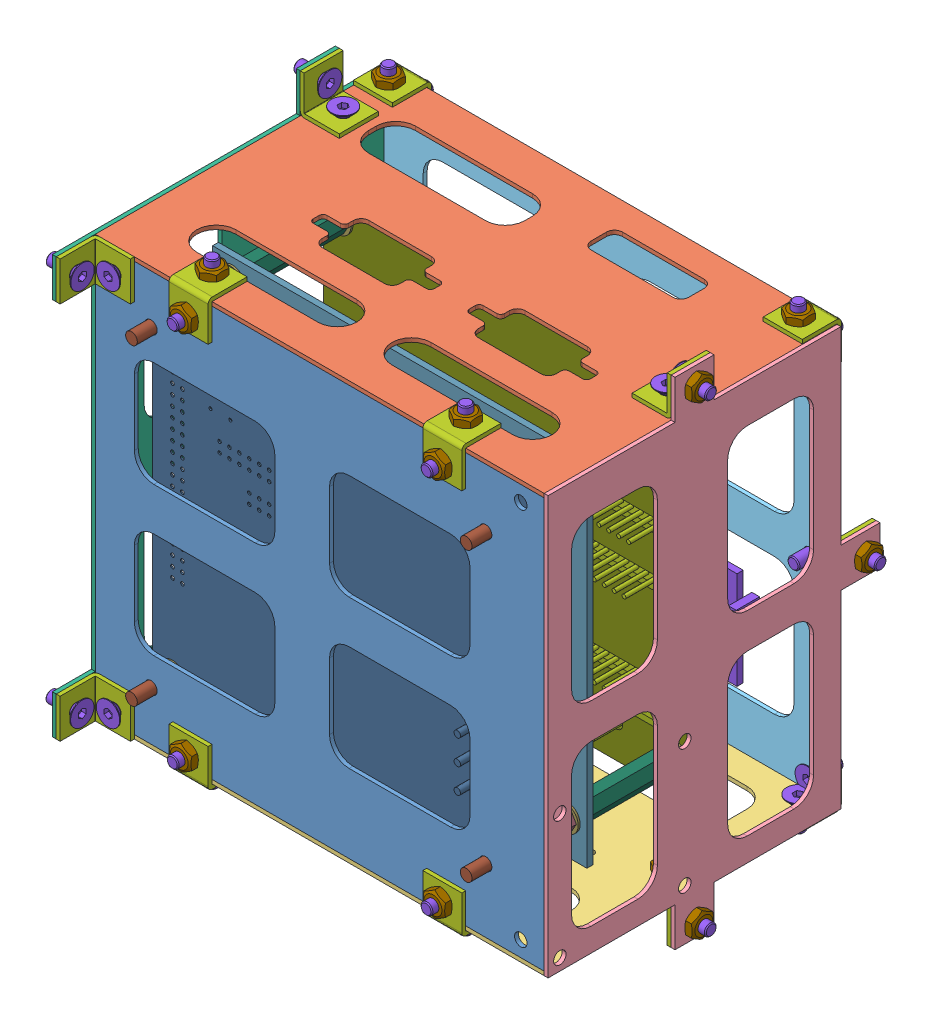
SolidWorks assembly avionics_reassemb, configuration Default. Lengths in mm.
Overall size (125.66 127 95).
175 component instances, 45 part files, 0 mates.
Components (placement in the parent):
- PCB_board_box_reassemb-1: PCB_board_box_reassemb [Default] at origin size (125.66 127 95)
  - PCB_board_box_buttom-1: PCB_board_box_buttom [Default] at origin size (115 105 1)
  - PCB_board_box_front-1: PCB_board_box_front [Default] at (0 53.5 -36.5) x (0 0 -1) z (0 -1 0) size (75 115 1)
  - PCB_board_box_back-1: PCB_board_box_back [Default] at (0 -53.5 -36.5) x (0 0 1) z (0 1 0) size (75 115 1)
  - PCB_board_box_right-1: PCB_board_box_right [Default] at (58.5 0 -36.5) x (0 0 1) z (-1 0 0) size (85 127 1)
  - PCB_board_box_top-1: PCB_board_box_top [Default] at (0 0 -74) x (0 -1 0) z (0 0 1) size (105 115 1)
  - PCB_board_box_left-1: PCB_board_box_left [Default] at (-57.5 0 -36.5) x (0 0 1) z (-1 0 0) size (85 127 1)
  - connector_1-1: connector_1 [Default] at (-32.5 49.6 2.1) x (1 0 0) z (0 0 -1) size (10 10 10)
  - connector_1-2: connector_1 [Default] at (57.5 58.5 -36.5) x (0 0 1) z (-1 0 0) size (10 10 10)
  - connector_1-3: connector_1 [Default] at (57.5 -58.5 -36.5) x (0 0 -1) z (-1 0 0) size (10 10 10)
  - connector_1-4: connector_1 [Default] at (32.5 -49.6 2.1) x (-1 0 0) z (0 0 -1) size (10 10 10)
  - connector_1-5: connector_1 [Default] at (-32.5 -49.6 2.1) x (-1 0 0) z (0 0 -1) size (10 10 10)
  - connector_1-6: connector_1 [Default] at (-57.5 48.5 6) x (0 1 0) z (1 0 0) size (10 10 10)
  - connector_1-7: connector_1 [Default] at (-57.5 -48.5 6) x (0 1 0) z (1 0 0) size (10 10 10)
  - connector_1-8: connector_1 [Default] at (-57.5 58.5 -56.5) x (0 0 -1) z (1 0 0) size (10 10 10)
  - connector_1-9: connector_1 [Default] at (-57.5 -58.5 -56.5) x (0 0 1) z (1 0 0) size (10 10 10)
  - connector_1-10: connector_1 [Default] at (52.5 0 -74) x (0 -1 0) z (0 0 -1) size (10 10 10)
  - connector_1-11: connector_1 [Default] at (52.5 -49.6 -75.1) size (10 10 10)
  - connector_1-12: connector_1 [Default] at (-52.5 -54.6 -70.1) x (-1 0 0) z (0 1 0) size (10 10 10)
  - connector_1-13: connector_1 [Default] at (-52.5 49.6 -75.1) x (-1 0 0) z (0 0 1) size (10 10 10)
  - connector_1-14: connector_1 [Default] at (32.5 49.6 2.1) x (1 0 0) z (0 0 -1) size (10 10 10)
  - connector_1-15: connector_1 [Default] at (52.5 49.6 -75.1) x (-1 0 0) z (0 0 1) size (10 10 10)
  - ISO 10642 - M3 x  8-1: ISO 10642 - M3 x  8 [Default] at (-52.5 48.6 -71.3293) x (0 0 -1) z (-1 0 0) size (8 6 6)
  - ISO 10642 - M3 x  8-2: ISO 10642 - M3 x  8 [Default] at (-52.5 50.8293 -69.1) x (0 1 0) z (-1 0 0) size (8 6 6)
  - ISO 10642 - M3 x  8-3: ISO 10642 - M3 x  8 [Default] at (-52.5 -48.6 -71.3293) x (0 0 -1) z (-1 0 0) size (8 6 6)
  - ISO 10642 - M3 x  8-4: ISO 10642 - M3 x  8 [Default] at (-52.5 -50.8293 -69.1) x (0 -1 0) z (-1 0 0) size (8 6 6)
  - ISO 10642 - M3 x  8-5: ISO 10642 - M3 x  8 [Default] at (52.5 -50.7586 -69.1) x (0 -1 0) z (-1 0 0) size (8 6 6)
  - ISO 10642 - M3 x  8-6: ISO 10642 - M3 x  8 [Default] at (52.5 -48.6 -71.2586) x (0 0 -1) z (-1 0 0) size (8 6 6)
  - ISO 10642 - M3 x  8-7: ISO 10642 - M3 x  8 [Default] at (32.5 -48.6 -1.7414) x (0 0 1) z (-1 0 0) size (8 6 6)
  - ISO 10642 - M3 x  8-8: ISO 10642 - M3 x  8 [Default] at (32.5 -50.7586 -3.9) x (0 -1 0) z (-1 0 0) size (8 6 6)
  - ISO 10642 - M3 x  8-9: ISO 10642 - M3 x  8 [Default] at (-32.5 -48.6 -1.7414) x (0 0 1) z (-1 0 0) size (8 6 6)
  - ISO 10642 - M3 x  8-10: ISO 10642 - M3 x  8 [Default] at (-32.5 -50.7586 -3.9) x (0 -1 0) z (-1 0 0) size (8 6 6)
  - ISO 10642 - M3 x  8-11: ISO 10642 - M3 x  8 [Default] at (32.5 48.6 -1.7414) x (0 0 1) z (-1 0 0) size (8 6 6)
  - ISO 10642 - M3 x  8-12: ISO 10642 - M3 x  8 [Default] at (32.5 50.7586 -3.9) x (0 1 0) z (-1 0 0) size (8 6 6)
  - ISO 10642 - M3 x  8-13: ISO 10642 - M3 x  8 [Default] at (-32.5 48.6 -1.6707) x (0 0 1) z (-1 0 0) size (8 6 6)
  - ISO 10642 - M3 x  8-14: ISO 10642 - M3 x  8 [Default] at (-32.5 50.7586 -3.9) x (0 1 0) z (-1 0 0) size (8 6 6)
  - ISO 10642 - M3 x  8-15: ISO 10642 - M3 x  8 [Default] at (52.5 48.6 -71.2586) x (0 0 -1) z (-1 0 0) size (8 6 6)
  - ISO 10642 - M3 x  8-16: ISO 10642 - M3 x  8 [Default] at (52.5 50.7586 -69.1) x (0 1 0) z (-1 0 0) size (8 6 6)
  - ISO 10642 - M3 x  8-17: ISO 10642 - M3 x  8 [Default] at (51.5 0 -76.7414) x (0 0 1) z (-1 0 0) size (8 6 6)
  - ISO 10642 - M3 x  8-18: ISO 10642 - M3 x  8 [Default] at (54.7586 0 -80) x (1 0 0) z (0 0 -1) size (8 6 6)
  - ISO 10642 - M3 x  8-19: ISO 10642 - M3 x  8 [Default] at (54.7586 -59.5 -36.5) x (1 0 0) z (0 0 -1) size (8 6 6)
  - ISO 10642 - M3 x  8-20: ISO 10642 - M3 x  8 [Default] at (51.5 -56.2414 -36.5) x (0 1 0) z (-1 0 0) size (8 6 6)
  - ISO 10642 - M3 x  8-21: ISO 10642 - M3 x  8 [Default] at (51.5 56.2414 -36.5) x (0 -1 0) z (-1 0 0) size (8 6 6)
  - ISO 10642 - M3 x  8-22: ISO 10642 - M3 x  8 [Default] at (54.8293 59.5 -36.5) x (1 0 0) z (0 0 -1) size (8 6 6)
  - ISO 10642 - M3 x  8-23: ISO 10642 - M3 x  8 [Default] at (-51.5 56.1707 -56.5) x (0 -1 0) z (-1 0 0) size (8 6 6)
  - ISO 10642 - M3 x  8-24: ISO 10642 - M3 x  8 [Default] at (-54.8293 59.5 -56.5) x (-1 0 0) z (0 0 1) size (8 6 6)
  - ISO 10642 - M3 x  8-25: ISO 10642 - M3 x  8 [Default] at (-51.5 48.5 3.7414) x (0 0 -1) z (-1 0 0) size (8 6 6)
  - ISO 10642 - M3 x  8-26: ISO 10642 - M3 x  8 [Default] at (-54.7586 48.5 7) x (-1 0 0) z (0 0 1) size (8 6 6)
  - ISO 10642 - M3 x  8-27: ISO 10642 - M3 x  8 [Default] at (-54.8293 -48.5 7) x (-1 0 0) z (0 0 1) size (8 6 6)
  - ISO 10642 - M3 x  8-28: ISO 10642 - M3 x  8 [Default] at (-51.5 -48.5 3.7414) x (0 0 -1) z (-1 0 0) size (8 6 6)
  - ISO 10642 - M3 x  8-29: ISO 10642 - M3 x  8 [Default] at (-54.7586 -59.5 -56.5) x (-1 0 0) z (0 0 1) size (8 6 6)
  - ISO 10642 - M3 x  8-30: ISO 10642 - M3 x  8 [Default] at (-51.5 -56.1707 -56.5) x (0 1 0) z (-1 0 0) size (8 6 6)
  - ISO 4032 - M3-1: ISO 4032 - M3 [Default] at (-52.5 48.6 -77.5) x (0 0 1) z (-1 0 0) size (2.4 6.35 5.5)
  - ISO 4032 - M3-2: ISO 4032 - M3 [Default] at (-52.5 54.6 -69.1) x (0 1 0) z (-1 0 0) size (2.4 6.35 5.5)
  - ISO 4032 - M3-3: ISO 4032 - M3 [Default] at (-51.5 52.5 -56.5) x (0 -1 0) z (-1 0 0) size (2.4 6.35 5.5)
  - ISO 4032 - M3-4: ISO 4032 - M3 [Default] at (-52.5 -48.6 -75.1) x (0 0 -1) z (-1 0 0) size (2.4 6.35 5.5)
  - ISO 4032 - M3-5: ISO 4032 - M3 [Default] at (-52.5 -54.6 -69.1) x (0 -1 0) z (-1 0 0) size (2.4 6.35 5.5)
  - ISO 4032 - M3-6: ISO 4032 - M3 [Default] at (-51.5 -52.5 -56.5) x (0 1 0) z (-1 0 0) size (2.4 6.35 5.5)
  - ISO 4032 - M3-7: ISO 4032 - M3 [Default] at (-51.5 -48.5 0) x (0 0 -1) z (-1 0 0) size (2.4 6.35 5.5)
  - ISO 4032 - M3-8: ISO 4032 - M3 [Default] at (-51.5 48.5 0) x (0 0 -1) z (-1 0 0) size (2.4 6.35 5.5)
  - ISO 4032 - M3-9: ISO 4032 - M3 [Default] at (-32.5 57 -3.9) x (0 -1 0) z (-1 0 0) size (2.4 6.35 5.5)
  - ISO 4032 - M3-10: ISO 4032 - M3 [Default] at (-32.5 48.6 4.5) x (0 0 -1) z (-1 0 0) size (2.4 6.35 5.5)
  - ISO 4032 - M3-11: ISO 4032 - M3 [Default] at (-32.5 -48.6 2.1) x (0 0 1) z (-1 0 0) size (2.4 6.35 5.5)
  - ISO 4032 - M3-12: ISO 4032 - M3 [Default] at (-32.5 -57 -3.9) x (0 1 0) z (-1 0 0) size (2.4 6.35 5.5)
  - ISO 4032 - M3-13: ISO 4032 - M3 [Default] at (52.5 -48.6 -75.1) x (0 0 -1) z (-1 0 0) size (2.4 6.35 5.5)
  - ISO 4032 - M3-14: ISO 4032 - M3 [Default] at (52.5 -54.6 -69.1) x (0 -1 0) z (-1 0 0) size (2.4 6.35 5.5)
  - ISO 4032 - M3-15: ISO 4032 - M3 [Default] at (52.5 48.6 -75.1) x (0 0 -1) z (-1 0 0) size (2.4 6.35 5.5)
  - ISO 4032 - M3-16: ISO 4032 - M3 [Default] at (52.5 54.6 -69.1) x (0 1 0) z (-1 0 0) size (2.4 6.35 5.5)
  - ISO 4032 - M3-17: ISO 4032 - M3 [Default] at (32.5 57 -3.9) x (0 -1 0) z (-1 0 0) size (2.4 6.35 5.5)
  - ISO 4032 - M3-18: ISO 4032 - M3 [Default] at (32.5 48.6 4.5) x (0 0 -1) z (-1 0 0) size (2.4 6.35 5.5)
  - ISO 4032 - M3-19: ISO 4032 - M3 [Default] at (32.5 -48.6 4.5) x (0 0 -1) z (-1 0 0) size (2.4 6.35 5.5)
  - ISO 4032 - M3-20: ISO 4032 - M3 [Default] at (32.5 -57 -3.9) x (0 1 0) z (-1 0 0) size (2.4 6.35 5.5)
  - ISO 4032 - M3-21: ISO 4032 - M3 [Default] at (51.5 -52.5 -36.5) x (0 1 0) z (-1 0 0) size (2.4 6.35 5.5)
  - ISO 4032 - M3-22: ISO 4032 - M3 [Default] at (51.5 52.5 -36.5) x (0 -1 0) z (-1 0 0) size (2.4 6.35 5.5)
  - ISO 4032 - M3-23: ISO 4032 - M3 [Default] at (58.5 0 -80) size (2.4 6.35 5.5)
  - ISO 4032 - M3-24: ISO 4032 - M3 [Default] at (58.5 -59.5 -36.5) size (2.4 6.35 5.5)
  - ISO 4032 - M3-25: ISO 4032 - M3 [Default] at (58.5 59.5 -36.5) size (2.4 6.35 5.5)
- PCB-1: PCB [Default] at (47.58 -45.05 -4.8556) x (0 1 0) z (0 0 -1) size (90.17 95.89 17.8)
- copper_pillar_M3_L15-1: copper_pillar_M3_L15 [Default] at (42.5 -36.16 0) x (1 0 0) z (0 1 0) size (5.77 16 5)
- copper_pillar_M3_L15-2: copper_pillar_M3_L15 [Default] at (-43.225 40.04 0) x (1 0 0) z (0 1 0) size (5.77 16 5)
- copper_pillar_M3_L15-3: copper_pillar_M3_L15 [Default] at (42.5 37.5 0) x (1 0 0) z (0 1 0) size (5.77 16 5)
- copper_pillar_M3_L15-4: copper_pillar_M3_L15 [Default] at (-43.225 -39.97 0) x (1 0 0) z (0 1 0) size (5.77 16 5)
- washerM3x0.5h-1: washerM3x0.5h [Default] at (-43.225 -39.97 -4.5) size (6.7 6.7 0.5)
- washerM3x0.5h-2: washerM3x0.5h [Default] at (42.5 -36.16 -4.5) size (6.7 6.7 0.5)
- washerM3x0.5h-3: washerM3x0.5h [Default] at (-43.225 40.04 -4) x (1 0 0) z (0 0 -1) size (6.7 6.7 0.5)
- washerM3x0.5h-4: washerM3x0.5h [Default] at (42.5 37.5 -4) x (1 0 0) z (0 0 -1) size (6.7 6.7 0.5)
- copper_pillar_M3_L15_1-1: copper_pillar_M3_L15_1 [Default] at (42.5 -36.16 -5.3556) x (1 0 0) z (0 1 0) size (5.77 26 5)
- copper_pillar_M3_L15_1-2: copper_pillar_M3_L15_1 [Default] at (42.5 37.5 -5.3556) x (1 0 0) z (0 1 0) size (5.77 26 5)
- copper_pillar_M3_L15_1-3: copper_pillar_M3_L15_1 [Default] at (-43.225 40.04 -5.3556) x (1 0 0) z (0 1 0) size (5.77 26 5)
- copper_pillar_M3_L15_1-4: copper_pillar_M3_L15_1 [Default] at (-43.225 -39.97 -5.3556) x (1 0 0) z (0 1 0) size (5.77 26 5)
- washerM3x0.5h-5: washerM3x0.5h [Default] at (-43.225 40.04 -5.3556) size (6.7 6.7 0.5)
- washerM3x0.5h-6: washerM3x0.5h [Default] at (-43.225 -39.97 -4.8556) x (1 0 0) z (0 0 -1) size (6.7 6.7 0.5)
- washerM3x0.5h-7: washerM3x0.5h [Default] at (42.5 -36.16 -4.8556) x (1 0 0) z (0 0 -1) size (6.7 6.7 0.5)
- washerM3x0.5h-8: washerM3x0.5h [Default] at (42.5 37.5 -4.8556) x (1 0 0) z (0 0 -1) size (6.7 6.7 0.5)
- washerM3x0.5h-9: washerM3x0.5h [Default] at (-43.225 40.04 -19.3556) x (1 0 0) z (0 0 -1) size (6.7 6.7 0.5)
- washerM3x0.5h-10: washerM3x0.5h [Default] at (-43.225 -39.97 -19.3556) x (1 0 0) z (0 0 -1) size (6.7 6.7 0.5)
- washerM3x0.5h-11: washerM3x0.5h [Default] at (42.5 -36.16 -19.3556) x (1 0 0) z (0 0 -1) size (6.7 6.7 0.5)
- washerM3x0.5h-12: washerM3x0.5h [Default] at (42.5 37.5 -19.3556) x (1 0 0) z (0 0 -1) size (6.7 6.7 0.5)
- STM32 Communication Board ver1.0-1: STM32 Communication Board ver1.0 [Default] at (42.5 -36.16 -21.3601) x (0 1 0) z (0 0 -1) size (90.17 95.89 10)
- washerM3x0.5h-13: washerM3x0.5h [Default] at (42.5 -36.16 -21.3601) x (1 0 0) z (0 0 -1) size (6.7 6.7 0.5)
- washerM3x0.5h-14: washerM3x0.5h [Default] at (-43.225 -39.97 -21.3601) x (1 0 0) z (0 0 -1) size (6.7 6.7 0.5)
- washerM3x0.5h-15: washerM3x0.5h [Default] at (42.5 37.5 -21.3601) x (1 0 0) z (0 0 -1) size (6.7 6.7 0.5)
- washerM3x0.5h-16: washerM3x0.5h [Default] at (-43.225 40.04 -21.3601) x (1 0 0) z (0 0 -1) size (6.7 6.7 0.5)
- copper_pillar_M3_L25_1-1: copper_pillar_M3_L25_1 [Default] at (-43.225 -39.97 -21.8601) x (1 0 0) z (0 1 0) size (5.77 37 5)
- copper_pillar_M3_L25_1-2: copper_pillar_M3_L25_1 [Default] at (42.5 -36.16 -21.8601) x (1 0 0) z (0 1 0) size (5.77 37 5)
- copper_pillar_M3_L25_1-3: copper_pillar_M3_L25_1 [Default] at (42.5 37.5 -21.8601) x (1 0 0) z (0 1 0) size (5.77 37 5)
- copper_pillar_M3_L25_1-4: copper_pillar_M3_L25_1 [Default] at (-43.225 40.04 -21.8601) x (1 0 0) z (0 1 0) size (5.77 37 5)
- washerM3x0.5h-17: washerM3x0.5h [Default] at (42.5 37.5 -47.3601) size (6.7 6.7 0.5)
- washerM3x0.5h-18: washerM3x0.5h [Default] at (-43.225 40.04 -46.8601) x (1 0 0) z (0 0 -1) size (6.7 6.7 0.5)
- washerM3x0.5h-19: washerM3x0.5h [Default] at (42.5 -36.16 -47.3601) size (6.7 6.7 0.5)
- washerM3x0.5h-20: washerM3x0.5h [Default] at (-43.225 -39.97 -47.3601) size (6.7 6.7 0.5)
- empty_board-1: empty_board [Default] at (0.08 0.12 -47.3601) x (0 1 0) z (-1 0 0) size (90 1.45 95)
- MTi-1_v3-1: MTi-1_v3 [Default] at (-8.5645 -18.7527 -51.9664) x (0 1 0) z (0 0 -1) size (53.34 66.07 22.31)
  - Board_1v2(2)^MTi-1-SoB_v2-1: Board_1v2(2)^MTi-1-SoB_v2 [Default] at origin size (12.15 12.15 1.56)
    - Open CASCADE STEP translator 6.8 2.1.1^Board_1v2(2)_MTi-1-SoB_v2-1: Open CASCADE STEP translator 6.8 2.1.1^Board_1v2(2)_MTi-1-SoB_v2 [Default] at (0 0 -1.5563) size (12.15 12.15 1.56)
      - Open CASCADE STEP translator 6.8 2.1.1.1^Open CASCADE STEP translator_ 6.8 2.1.1_Board_1v2(2)_MTi-1-SoB_v2-1: Open CASCADE STEP translator 6.8 2.1.1.1^Open CASCADE STEP translator_ 6.8 2.1.1_Board_1v2(2)_MTi-1-SoB_v2 [Default] at origin size (12.15 12.15 1.56)
  - U200_1v2(2)^MTi-1-SoB_v2-1: U200_1v2(2)^MTi-1-SoB_v2 [Default] at origin size (3.1 3.3 0.6)
    - 7460079024(2)^U200_1v2(2)_MTi-1-SoB_v2-1: 7460079024(2)^U200_1v2(2)_MTi-1-SoB_v2 [Default] at (5.6 3.4 0) size (3.1 3.3 0.6)
      - Extruded(2)^7460079024(2)_U200_1v2(2)_MTi-1-SoB_v2-1: Extruded(2)^7460079024(2)_U200_1v2(2)_MTi-1-SoB_v2 [Default] at origin size (3.1 3.3 0.6)
  - C200_1v2(2)^MTi-1-SoB_v2-1: C200_1v2(2)^MTi-1-SoB_v2 [Default] at origin size (1.05 0.55 0.55)
    - Cap_0402(2)^C200_1v2(2)_MTi-1-SoB_v2-1: Cap_0402(2)^C200_1v2(2)_MTi-1-SoB_v2 [Default] at (5.3999 6.9749 0.26) x (-1 0 0) z (0 0 1) size (1.05 0.55 0.55)
  - C201_1v2(2)^MTi-1-SoB_v2-1: C201_1v2(2)^MTi-1-SoB_v2 [Default] at origin size (1.05 0.55 0.55)
    - Cap_0402(2)^C201_1v2(2)_MTi-1-SoB_v2-1: Cap_0402(2)^C201_1v2(2)_MTi-1-SoB_v2 [Default] at (6.7999 1.375 0.26) x (-1 0 0) z (0 0 1) size (1.05 0.55 0.55)
  - C204_1v2(2)^MTi-1-SoB_v2-1: C204_1v2(2)^MTi-1-SoB_v2 [Default] at origin size (1.05 0.55 0.55)
    - Cap_0402(2)^C204_1v2(2)_MTi-1-SoB_v2-1: Cap_0402(2)^C204_1v2(2)_MTi-1-SoB_v2 [Default] at (8.1999 3.0749 0.26) x (-1 0 0) z (0 0 1) size (1.05 0.55 0.55)
  - C205_1v2(2)^MTi-1-SoB_v2-1: C205_1v2(2)^MTi-1-SoB_v2 [Default] at origin size (1.05 0.55 0.55)
    - Cap_0402(2)^C205_1v2(2)_MTi-1-SoB_v2-1: Cap_0402(2)^C205_1v2(2)_MTi-1-SoB_v2 [Default] at (4.2001 0.8251 0.26) x (1 0 0) z (0 0 1) size (1.05 0.55 0.55)
  - C206_1v2(2)^MTi-1-SoB_v2-1: C206_1v2(2)^MTi-1-SoB_v2 [Default] at origin size (0.55 1.05 0.55)
    - Cap_0402(2)^C206_1v2(2)_MTi-1-SoB_v2-1: Cap_0402(2)^C206_1v2(2)_MTi-1-SoB_v2 [Default] at (3.1251 4.5999 0.26) x (0 -1 0) z (0 0 1) size (1.05 0.55 0.55)
  - C207_1v2(2)^MTi-1-SoB_v2-1: C207_1v2(2)^MTi-1-SoB_v2 [Default] at origin size (1.05 0.55 0.55)
    - Cap_0402(2)^C207_1v2(2)_MTi-1-SoB_v2-1: Cap_0402(2)^C207_1v2(2)_MTi-1-SoB_v2 [Default] at (7.3001 5.4251 0.26) x (1 0 0) z (0 0 1) size (1.05 0.55 0.55)
  - C208_1v2(2)^MTi-1-SoB_v2-1: C208_1v2(2)^MTi-1-SoB_v2 [Default] at origin size (0.55 1.05 0.55)
    - Cap_0402(2)^C208_1v2(2)_MTi-1-SoB_v2-1: Cap_0402(2)^C208_1v2(2)_MTi-1-SoB_v2 [Default] at (3.1251 2.5999 0.26) x (0 -1 0) z (0 0 1) size (1.05 0.55 0.55)
  - C209_1v2(2)^MTi-1-SoB_v2-1: C209_1v2(2)^MTi-1-SoB_v2 [Default] at origin size (1.05 0.55 0.55)
    - Cap_0402(2)^C209_1v2(2)_MTi-1-SoB_v2-1: Cap_0402(2)^C209_1v2(2)_MTi-1-SoB_v2 [Default] at (8.6001 1.4251 0.26) x (1 0 0) z (0 0 1) size (1.05 0.55 0.55)
  - C300_1v2(2)^MTi-1-SoB_v2-1: C300_1v2(2)^MTi-1-SoB_v2 [Default] at origin size (0.55 1.05 0.55)
    - Cap_0402(2)^C300_1v2(2)_MTi-1-SoB_v2-1: Cap_0402(2)^C300_1v2(2)_MTi-1-SoB_v2 [Default] at (10.425 8.2999 0.26) x (0 -1 0) z (0 0 1) size (1.05 0.55 0.55)
  - C301_1v2(2)^MTi-1-SoB_v2-1: C301_1v2(2)^MTi-1-SoB_v2 [Default] at origin size (1.05 0.55 0.55)
    - Cap_0402(2)^C301_1v2(2)_MTi-1-SoB_v2-1: Cap_0402(2)^C301_1v2(2)_MTi-1-SoB_v2 [Default] at (3.4001 10.375 0.26) x (1 0 0) z (0 0 1) size (1.05 0.55 0.55)
  - C302_1v2(2)^MTi-1-SoB_v2-1: C302_1v2(2)^MTi-1-SoB_v2 [Default] at origin size (1.05 0.55 0.55)
    - Cap_0402(2)^C302_1v2(2)_MTi-1-SoB_v2-1: Cap_0402(2)^C302_1v2(2)_MTi-1-SoB_v2 [Default] at (5.5999 8.0749 0.26) x (-1 0 0) z (0 0 1) size (1.05 0.55 0.55)
  - C303_1v2(2)^MTi-1-SoB_v2-1: C303_1v2(2)^MTi-1-SoB_v2 [Default] at origin size (1.05 0.55 0.55)
    - Cap_0402(2)^C303_1v2(2)_MTi-1-SoB_v2-1: Cap_0402(2)^C303_1v2(2)_MTi-1-SoB_v2 [Default] at (7.2999 6.9749 0.26) x (-1 0 0) z (0 0 1) size (1.05 0.55 0.55)
  - C305_1v2(2)^MTi-1-SoB_v2-1: C305_1v2(2)^MTi-1-SoB_v2 [Default] at origin size (0.55 1.05 0.55)
    - Cap_0402(2)^C305_1v2(2)_MTi-1-SoB_v2-1: Cap_0402(2)^C305_1v2(2)_MTi-1-SoB_v2 [Default] at (6.4749 9.3001 0.26) x (0 1 0) z (0 0 1) size (1.05 0.55 0.55)
  - C304_1v2(2)^MTi-1-SoB_v2-1: C304_1v2(2)^MTi-1-SoB_v2 [Default] at origin size (0.55 1.05 0.55)
    - Cap_0402(2)^C304_1v2(2)_MTi-1-SoB_v2-1: Cap_0402(2)^C304_1v2(2)_MTi-1-SoB_v2 [Default] at (5.4749 9.3001 0.26) x (0 1 0) z (0 0 1) size (1.05 0.55 0.55)
  - R200_1v2(2)^MTi-1-SoB_v2-1: R200_1v2(2)^MTi-1-SoB_v2 [Default] at origin size (1 0.5 0.35)
    - RES0402(2)^R200_1v2(2)_MTi-1-SoB_v2-1: RES0402(2)^R200_1v2(2)_MTi-1-SoB_v2 [Default] at (-16.787 18.2331 0) x (-1 0 0) z (0 1 0) size (1 0.35 0.5)
  - R300_1v2(2)^MTi-1-SoB_v2-1: R300_1v2(2)^MTi-1-SoB_v2 [Default] at origin size (0.5 1 0.35)
    - RES0402(2)^R300_1v2(2)_MTi-1-SoB_v2-1: RES0402(2)^R300_1v2(2)_MTi-1-SoB_v2 [Default] at (13.6331 30.587 0) x (0 1 0) z (1 0 0) size (1 0.35 0.5)
  - R301_1v2(2)^MTi-1-SoB_v2-1: R301_1v2(2)^MTi-1-SoB_v2 [Default] at origin size (0.5 1 0.35)
    - RES0402(2)^R301_1v2(2)_MTi-1-SoB_v2-1: RES0402(2)^R301_1v2(2)_MTi-1-SoB_v2 [Default] at (21.9331 28.487 0) x (0 1 0) z (1 0 0) size (1 0.35 0.5)
  - S300_1v2(2)^MTi-1-SoB_v2-1: S300_1v2(2)^MTi-1-SoB_v2 [Default] at origin size (3 3 1)
    - 6752205952(2)^S300_1v2(2)_MTi-1-SoB_v2-1: 6752205952(2)^S300_1v2(2)_MTi-1-SoB_v2 [Default] at (8.4999 8.8999 0) size (3 3 1)
      - Extruded-1(2)^6752205952(2)_S300_1v2(2)_MTi-1-SoB_v2-1: Extruded-1(2)^6752205952(2)_S300_1v2(2)_MTi-1-SoB_v2 [Default] at origin size (3 3 1)
  - S301_1v2(2)^MTi-1-SoB_v2-1: S301_1v2(2)^MTi-1-SoB_v2 [Default] at origin size (2.5 3 0.86)
    - User_Library-LGA-14_2_5x3(2)^S301_1v2(2)_MTi-1-SoB_v2-1: User_Library-LGA-14_2_5x3(2)^S301_1v2(2)_MTi-1-SoB_v2 [Default] at (3.1 8.3 0.85) x (0 -1 0) z (1 0 0) size (3 0.86 2.5)
  - R302_1v2(2)^MTi-1-SoB_v2-1: R302_1v2(2)^MTi-1-SoB_v2 [Default] at origin size (0.5 1 0.35)
    - RES0402(2)^R302_1v2(2)_MTi-1-SoB_v2-1: RES0402(2)^R302_1v2(2)_MTi-1-SoB_v2 [Default] at (22.9331 28.487 0) x (0 1 0) z (1 0 0) size (1 0.35 0.5)
  - C202_1v2(2)^MTi-1-SoB_v2-1: C202_1v2(2)^MTi-1-SoB_v2 [Default] at origin size (1.05 0.55 0.55)
    - Cap_0402(2)^C202_1v2(2)_MTi-1-SoB_v2-1: Cap_0402(2)^C202_1v2(2)_MTi-1-SoB_v2 [Default] at (8.2001 4.4251 0.26) x (1 0 0) z (0 0 1) size (1.05 0.55 0.55)
  - C203_1v2(2)^MTi-1-SoB_v2-1: C203_1v2(2)^MTi-1-SoB_v2 [Default] at origin size (1.05 0.55 0.55)
    - Cap_0402(2)^C203_1v2(2)_MTi-1-SoB_v2-1: Cap_0402(2)^C203_1v2(2)_MTi-1-SoB_v2 [Default] at (8.2001 3.4251 0.26) x (1 0 0) z (0 0 1) size (1.05 0.55 0.55)
  - Y200_1v2(2)^MTi-1-SoB_v2-1: Y200_1v2(2)^MTi-1-SoB_v2 [Default] at origin size (1.61 2.01 0.31)
    - User_Library-Crystal_(NDK)_2.0x1.6(2)^Y200_1v2(2)_MTi-1-SoB_v2-1: User_Library-Crystal_(NDK)_2.0x1.6(2)^Y200_1v2(2)_MTi-1-SoB_v2 [Default] at (10.2 4.0001 0) x (0 -1 0) z (-1 0 0) size (2.01 0.31 1.61)
  - R303_1v2(2)^MTi-1-SoB_v2-1: R303_1v2(2)^MTi-1-SoB_v2 [Default] at origin size (0.5 1 0.35)
    - RES0402(2)^R303_1v2(2)_MTi-1-SoB_v2-1: RES0402(2)^R303_1v2(2)_MTi-1-SoB_v2 [Default] at (-1.8331 -11.987 0) x (0 -1 0) z (-1 0 0) size (1 0.35 0.5)
  - Mti-7 development board-1: Mti-7 development board [Default] at (6.7227 17.82 -3.1563) x (1 0 0) z (0 -1 0) size (53.34 18.51 57.52)
  - GNSS_board-1: GNSS_board [Default] at (6.6927 40.5245 6.9537) size (25 37 6)
- ISO 4032 - M3-1: ISO 4032 - M3 [Default] at (-43.225 -39.97 -48.8101) x (0 0 -1) z (1 0 0) size (2.4 6.35 5.5)
- ISO 4032 - M3-2: ISO 4032 - M3 [Default] at (-43.225 40.04 -48.8101) x (0 0 -1) z (1 0 0) size (2.4 6.35 5.5)
- ISO 4032 - M3-3: ISO 4032 - M3 [Default] at (42.5 -36.16 -50.4101) x (0 0 -1) z (1 0 0) size (2.4 6.35 5.5)
- ISO 4032 - M3-4: ISO 4032 - M3 [Default] at (42.5 37.5 -48.8101) x (0 0 -1) z (1 0 0) size (2.4 6.35 5.5)
- CUI_DEVICES_CFM-4010V-070-273-1: CUI_DEVICES_CFM-4010V-070-273 [Default] at (58.5 -34.5 -18) x (0 -1 0) z (0 0 1) size (0.06 0.01 0.07)
